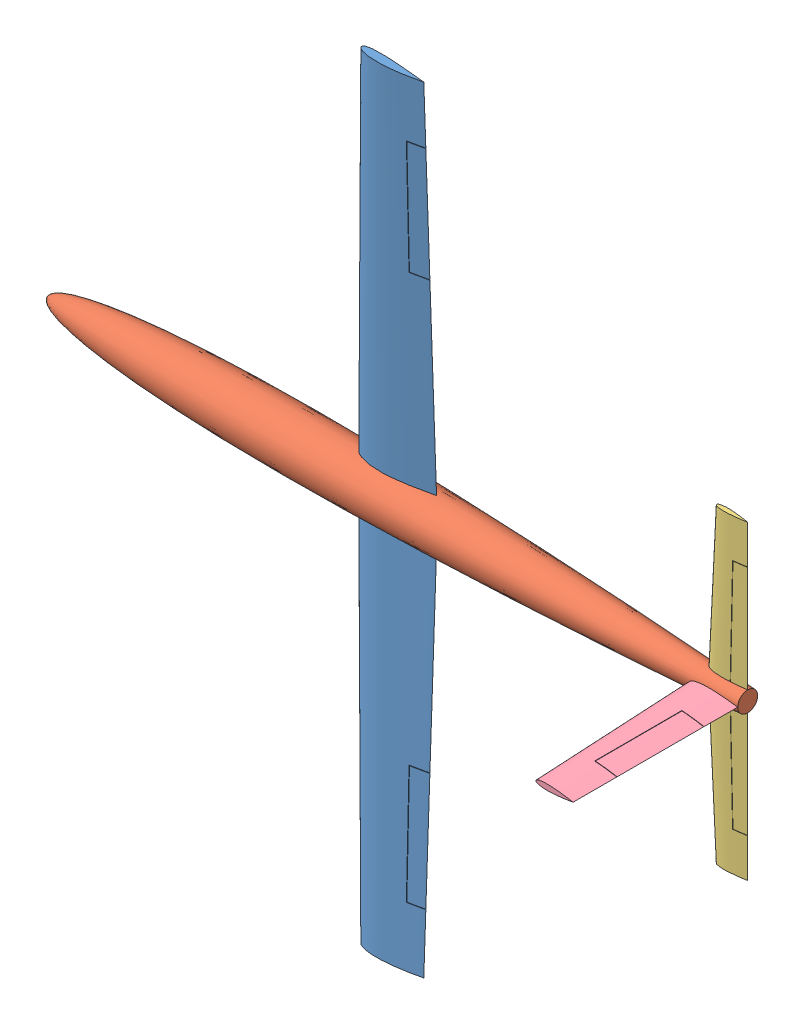
SolidWorks assembly kiteAssembly_FS, configuration Default. Lengths in mm.
Overall size (9020.01 10000.08 2580.39).
4 component instances, 4 part files, 12 mates.
Components (placement in the parent):
- wing_FS-1: wing_FS [Default] x (1 0 0) z (0 0 -1) size (1000.26 10000.08 307.21)
- fuselage_FS-1: fuselage_FS [Default] at (-4020 0 0) size (9020 660.77 660.77)
- hStab_FS-1: hStab_FS [Default] at (4500 0 0) size (500.02 4000.02 75.08)
- vStab_FS-1: vStab_FS [Default] at (4400 0 0) x (1 0 0) z (0 -1 0) size (600.01 2250.01 90.12)
Mates (geometry in assembly coordinates):
- Distance2: distance = 0 mm: plane of assembly through (0 0 0) normal (0 0 1); plane of assembly; plane of wing_FS-1 through (0 0 0) normal (0 0 -1)
- Distance3: distance = 0 mm: plane of assembly through (0 0 0) normal (0 1 0); plane of assembly; plane of wing_FS-1 through (0 0 0) normal (0 -1 0)
- Distance4: distance = 0 mm: plane of assembly through (0 0 0) normal (1 0 0); plane of assembly; plane of wing_FS-1 through (0 0 0) normal (1 0 0)
- Distance5: distance = 0 mm anti-aligned: plane of wing_FS-1 through (0 0 0) normal (0 0 -1); plane of fuselage_FS-1 through (-4020 0 0) normal (0 0 1)
- Distance6: distance = 0 mm anti-aligned: plane of wing_FS-1 through (0 0 0) normal (0 -1 0); plane of fuselage_FS-1 through (-4020 0 0) normal (0 1 0)
- Distance7: distance = 0 mm anti-aligned: plane of hStab_FS-1 through (4500 0 0) normal (0 0 1); plane of wing_FS-1 through (0 0 0) normal (0 0 -1)
- Distance8: distance = 0 mm anti-aligned: plane of wing_FS-1 through (0 0 0) normal (0 -1 0); plane of hStab_FS-1 through (4500 0 0) normal (0 1 0)
- Distance9: distance = 0 mm aligned: plane of hStab_FS-1 through (5000 0 0) normal (1 0 0); plane of fuselage_FS-1 through (5000 0 0) normal (1 0 0)
- Distance10: distance = 0 mm aligned: plane of vStab_FS-1 through (4400 0 0) normal (0 -1 0); plane of wing_FS-1 through (0 0 0) normal (0 -1 0)
- Distance11: distance = 0 mm anti-aligned: plane of wing_FS-1 through (0 0 0) normal (0 0 -1); plane of vStab_FS-1 through (4400 0 0) normal (0 0 1)
- Distance12: distance = 0 mm aligned: plane of vStab_FS-1 through (5000 0 0) normal (1 0 0); plane of fuselage_FS-1 through (5000 0 0) normal (1 0 0)
- Distance14: distance = 0 mm aligned: plane of hStab_FS-1 through (4500 0 0) normal (1 0 0)
